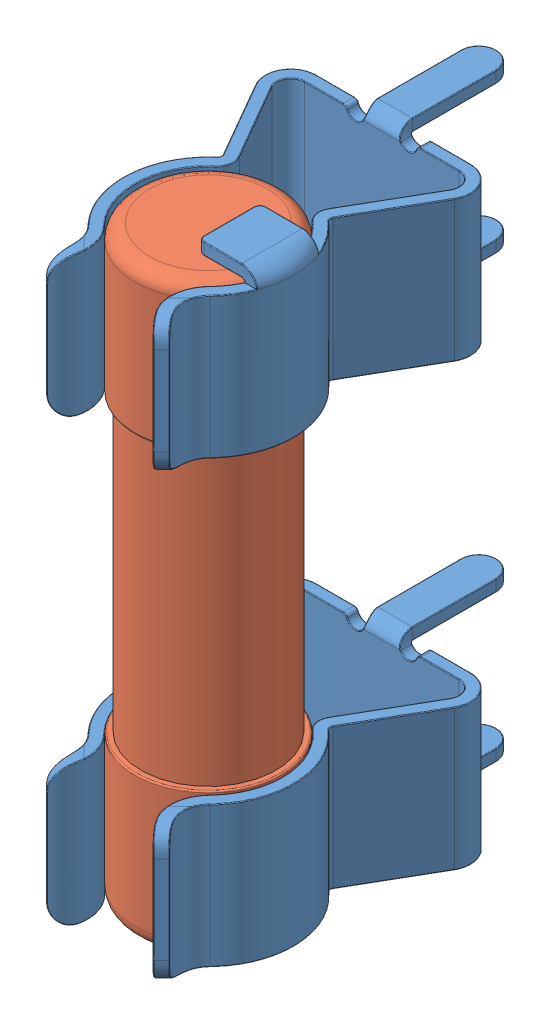
SolidWorks assembly User Library-Clips FH-100 with fuse 5x20, configuration Default. Lengths in mm.
Overall size (7 20.81 13.49).
3 component instances, 2 part files, 0 mates.
Components (placement in the parent):
- User Library-Clips FH-100 with fuse 5x20_FH-100-1: User Library-Clips FH-100 with fuse 5x20_FH-100 [Default] at (0 -7.5 0) size (7 5.61 13.49)
- User Library-Clips FH-100 with fuse 5x20_FH-100-2: User Library-Clips FH-100 with fuse 5x20_FH-100 [Default] at (0 7.5 0) x (-1 0 0) z (0 0 1) size (7 5.61 13.49)
- User Library-Clips FH-100 with fuse 5x20_5x20-1: User Library-Clips FH-100 with fuse 5x20_5x20 [Default] at (0 0 6.3) x (-0.997975 0 -0.063612) z (0 -1 0) size (5 5 20)
